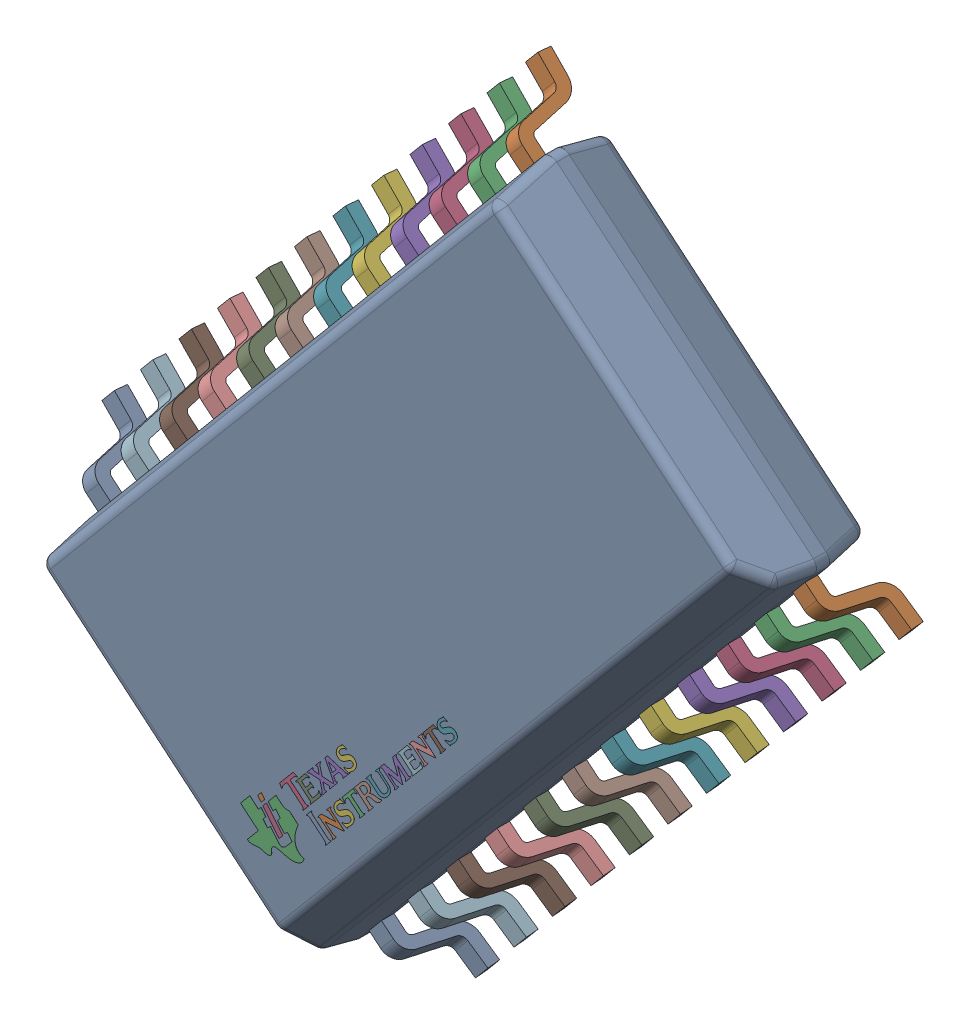
SolidWorks assembly U6, configuration Défaut. Lengths in mm.
Overall size (17.82 18.44 2.65).
28 component instances, 4 part files, 0 mates.
Components (placement in the parent):
- IC_Texas_Instruments_CD74HC4067M96_eec-1: IC_Texas_Instruments_CD74HC4067M96_eec [Défaut] at (19.685 20.828 0) x (0.766044 -0.642788 0) z (0 0 1) size (10.34 15.4 2.65)
  - BODY-SO-1: BODY-SO [Défaut] at (0 0 1.0825) x (0 1 0) z (1 0 0) size (15.4 2.45 7.5)
  - LEAD-SO-1: LEAD-SO [Défaut] at (4.315 6.985 0.25) x (0 1 0) z (1 0 0) size (0.41 1.43 1.42)
  - LEAD-SO-2: LEAD-SO [Défaut] at (4.315 5.715 0.25) x (0 1 0) z (1 0 0) size (0.41 1.43 1.42)
  - LEAD-SO-3: LEAD-SO [Défaut] at (4.315 4.445 0.25) x (0 1 0) z (1 0 0) size (0.41 1.43 1.42)
  - LEAD-SO-4: LEAD-SO [Défaut] at (4.315 3.175 0.25) x (0 1 0) z (1 0 0) size (0.41 1.43 1.42)
  - LEAD-SO-5: LEAD-SO [Défaut] at (4.315 1.905 0.25) x (0 1 0) z (1 0 0) size (0.41 1.43 1.42)
  - LEAD-SO-6: LEAD-SO [Défaut] at (4.315 0.635 0.25) x (0 1 0) z (1 0 0) size (0.41 1.43 1.42)
  - LEAD-SO-7: LEAD-SO [Défaut] at (4.315 -0.635 0.25) x (0 1 0) z (1 0 0) size (0.41 1.43 1.42)
  - LEAD-SO-8: LEAD-SO [Défaut] at (4.315 -1.905 0.25) x (0 1 0) z (1 0 0) size (0.41 1.43 1.42)
  - LEAD-SO-9: LEAD-SO [Défaut] at (4.315 -3.175 0.25) x (0 1 0) z (1 0 0) size (0.41 1.43 1.42)
  - LEAD-SO-10: LEAD-SO [Défaut] at (4.315 -4.445 0.25) x (0 1 0) z (1 0 0) size (0.41 1.43 1.42)
  - LEAD-SO-11: LEAD-SO [Défaut] at (4.315 -5.715 0.25) x (0 1 0) z (1 0 0) size (0.41 1.43 1.42)
  - LEAD-SO-12: LEAD-SO [Défaut] at (4.315 -6.985 0.25) x (0 1 0) z (1 0 0) size (0.41 1.43 1.42)
  - LEAD-SO-13: LEAD-SO [Défaut] at (-4.315 6.985 0.25) x (0 -1 0) z (-1 0 0) size (0.41 1.43 1.42)
  - LEAD-SO-14: LEAD-SO [Défaut] at (-4.315 5.715 0.25) x (0 -1 0) z (-1 0 0) size (0.41 1.43 1.42)
  - LEAD-SO-15: LEAD-SO [Défaut] at (-4.315 4.445 0.25) x (0 -1 0) z (-1 0 0) size (0.41 1.43 1.42)
  - LEAD-SO-16: LEAD-SO [Défaut] at (-4.315 3.175 0.25) x (0 -1 0) z (-1 0 0) size (0.41 1.43 1.42)
  - LEAD-SO-17: LEAD-SO [Défaut] at (-4.315 1.905 0.25) x (0 -1 0) z (-1 0 0) size (0.41 1.43 1.42)
  - LEAD-SO-18: LEAD-SO [Défaut] at (-4.315 0.635 0.25) x (0 -1 0) z (-1 0 0) size (0.41 1.43 1.42)
  - LEAD-SO-19: LEAD-SO [Défaut] at (-4.315 -0.635 0.25) x (0 -1 0) z (-1 0 0) size (0.41 1.43 1.42)
  - LEAD-SO-20: LEAD-SO [Défaut] at (-4.315 -1.905 0.25) x (0 -1 0) z (-1 0 0) size (0.41 1.43 1.42)
  - LEAD-SO-21: LEAD-SO [Défaut] at (-4.315 -3.175 0.25) x (0 -1 0) z (-1 0 0) size (0.41 1.43 1.42)
  - LEAD-SO-22: LEAD-SO [Défaut] at (-4.315 -4.445 0.25) x (0 -1 0) z (-1 0 0) size (0.41 1.43 1.42)
  - LEAD-SO-23: LEAD-SO [Défaut] at (-4.315 -5.715 0.25) x (0 -1 0) z (-1 0 0) size (0.41 1.43 1.42)
  - LEAD-SO-24: LEAD-SO [Défaut] at (-4.315 -6.985 0.25) x (0 -1 0) z (-1 0 0) size (0.41 1.43 1.42)
  - Texas Logo Yury-1: Texas Logo Yury [Défaut] at (2.174 -7.1221 2.551) x (0 1 0) z (0 0 1) size (1.32 1.29 0.11)
  - Texas Logo Yury - Copy-1: Texas Logo Yury - Copy [Défaut] at (2.0641 -7.1534 2.551) x (0 1 0) z (0 0 1) size (4.61 1.2 0.1)
